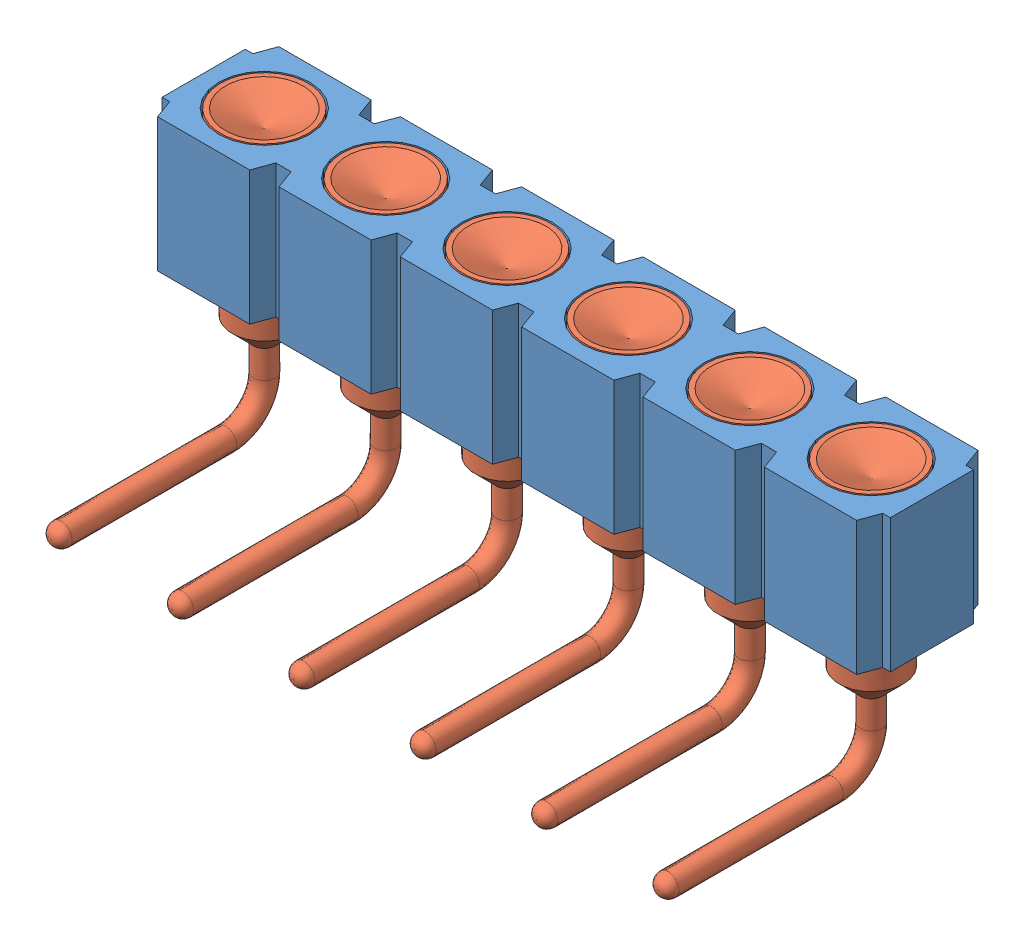
SolidWorks assembly mill-max-399-10-106-10-007000, configuration Default. Lengths in mm.
Overall size (15.24 5.81 5.74).
7 component instances, 2 part files, 0 mates.
Components (placement in the parent):
- mill-max-399-10-106-10-007000_P3XX-11-010-00-000000(P306-11-010-00-000000)-1: mill-max-399-10-106-10-007000_P3XX-11-010-00-000000(P306-11-010-00-000000) [Default] at (-56.7488 -1.0694 1.27) size (15.24 2.79 2.54)
- mill-max-399-10-106-10-007000_1960(1960-0-00-15-00-00-03-0)-1: mill-max-399-10-106-10-007000_1960(1960-0-00-15-00-00-03-0) [Default] at (-50.7044 -1.0694 0) x (0 -1 0) z (1 0 0) size (5.81 5.38 1.83)
- mill-max-399-10-106-10-007000_1960(1960-0-00-15-00-00-03-0)-2: mill-max-399-10-106-10-007000_1960(1960-0-00-15-00-00-03-0) [Default] at (-43.0844 -1.0694 0) x (0 -1 0) z (1 0 0) size (5.81 5.38 1.83)
- mill-max-399-10-106-10-007000_1960(1960-0-00-15-00-00-03-0)-3: mill-max-399-10-106-10-007000_1960(1960-0-00-15-00-00-03-0) [Default] at (-55.7844 -1.0694 0) x (0 -1 0) z (1 0 0) size (5.81 5.38 1.83)
- mill-max-399-10-106-10-007000_1960(1960-0-00-15-00-00-03-0)-4: mill-max-399-10-106-10-007000_1960(1960-0-00-15-00-00-03-0) [Default] at (-48.1644 -1.0694 0) x (0 -1 0) z (1 0 0) size (5.81 5.38 1.83)
- mill-max-399-10-106-10-007000_1960(1960-0-00-15-00-00-03-0)-5: mill-max-399-10-106-10-007000_1960(1960-0-00-15-00-00-03-0) [Default] at (-53.2444 -1.0694 0) x (0 -1 0) z (1 0 0) size (5.81 5.38 1.83)
- mill-max-399-10-106-10-007000_1960(1960-0-00-15-00-00-03-0)-6: mill-max-399-10-106-10-007000_1960(1960-0-00-15-00-00-03-0) [Default] at (-45.6244 -1.0694 0) x (0 -1 0) z (1 0 0) size (5.81 5.38 1.83)
